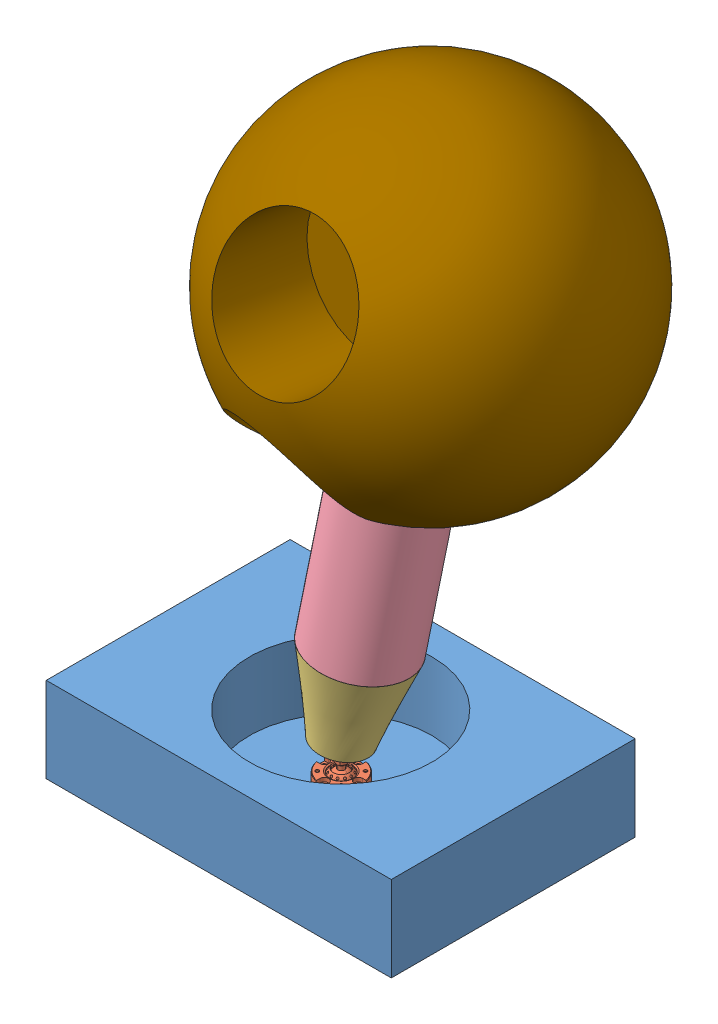
SolidWorks assembly full_model1, configuration Default. Lengths in mm.
Overall size (254.38 392.52 231.48).
52 component instances, 9 part files, 21 mates.
Components (placement in the parent):
- torso-1: torso [Default] x (-1 0 0) z (0 0 -1) size (202.29 50 142.99)
- SR JOINT - SRJ006C-1: SR JOINT - SRJ006C [Default] at (0.3693 15.1617 0) x (0 -1 0) z (0 0 1) size (26.94 25.01 25.01)
- cone-1: cone [Default] at (7.2631 84.0209 -4.0174) x (-0.271209 0.115653 0.955547) z (0.952594 -0.109957 0.283679) size (57.45 50 58.36)
- neck-1: neck [Default] at (21.0508 182.7394 -12.0523) x (0.07218 -0.090923 -0.993239) z (-0.987816 0.131145 -0.083791) size (55 152.51 55)
- 4200-2: 4200 [Default] at (40.0164 210.3951 -13.2057) x (-0.987816 0.131145 -0.083791) z (-0.15192 -0.929416 0.336313) size (14 30.03 30.03)
  - 4200_3-1: 4200_3 [Default] at (3.5 -8.0902 -5.8779) size (4.76 4.76 4.76)
  - 4200_3-2: 4200_3 [Default] at (3.5 -3.0902 -9.5106) size (4.76 4.76 4.76)
  - 4200_3-3: 4200_3 [Default] at (3.5 3.0902 -9.5106) size (4.76 4.76 4.76)
  - 4200_3-4: 4200_3 [Default] at (3.5 8.0902 -5.8779) size (4.76 4.76 4.76)
  - 4200_3-5: 4200_3 [Default] at (3.5 10 0) size (4.76 4.76 4.76)
  - 4200_3-6: 4200_3 [Default] at (3.5 8.0902 5.8779) size (4.76 4.76 4.76)
  - 4200_3-7: 4200_3 [Default] at (3.5 3.0902 9.5106) size (4.76 4.76 4.76)
  - 4200_3-8: 4200_3 [Default] at (3.5 -3.0902 9.5106) size (4.76 4.76 4.76)
  - 4200_3-9: 4200_3 [Default] at (3.5 -8.0902 5.8779) size (4.76 4.76 4.76)
  - 4200_3-10: 4200_3 [Default] at (3.5 -10 0) size (4.76 4.76 4.76)
  - 4200_3-11: 4200_3 [Default] at (10.5 -8.0902 -5.8779) size (4.76 4.76 4.76)
  - 4200_3-12: 4200_3 [Default] at (10.5 -3.0902 -9.5106) size (4.76 4.76 4.76)
  - 4200_3-13: 4200_3 [Default] at (10.5 3.0902 -9.5106) size (4.76 4.76 4.76)
  - 4200_3-14: 4200_3 [Default] at (10.5 8.0902 -5.8779) size (4.76 4.76 4.76)
  - 4200_3-15: 4200_3 [Default] at (10.5 10 0) size (4.76 4.76 4.76)
  - 4200_3-16: 4200_3 [Default] at (10.5 8.0902 5.8779) size (4.76 4.76 4.76)
  - 4200_3-17: 4200_3 [Default] at (10.5 3.0902 9.5106) size (4.76 4.76 4.76)
  - 4200_3-18: 4200_3 [Default] at (10.5 -3.0902 9.5106) size (4.76 4.76 4.76)
  - 4200_3-19: 4200_3 [Default] at (10.5 -8.0902 5.8779) size (4.76 4.76 4.76)
  - 4200_3-20: 4200_3 [Default] at (10.5 -10 0) size (4.76 4.76 4.76)
  - 4200_24-1: 4200_24 [Default] at (14 0 0) x (-1 0 0) z (0 0 1) size (14 30.03 30.03)
  - 4200_26-1: 4200_26 [Default] at origin size (14 17 17)
- 4200-1: 4200 [Default] at (24.1897 212.4963 -14.5482) x (-0.987816 0.131145 -0.083791) z (-0.010835 0.479146 0.877668) size (14 30.03 30.03)
  - 4200_3-1: 4200_3 [Default] at (3.5 -8.0902 -5.8779) size (4.76 4.76 4.76)
  - 4200_3-2: 4200_3 [Default] at (3.5 -3.0902 -9.5106) size (4.76 4.76 4.76)
  - 4200_3-3: 4200_3 [Default] at (3.5 3.0902 -9.5106) size (4.76 4.76 4.76)
  - 4200_3-4: 4200_3 [Default] at (3.5 8.0902 -5.8779) size (4.76 4.76 4.76)
  - 4200_3-5: 4200_3 [Default] at (3.5 10 0) size (4.76 4.76 4.76)
  - 4200_3-6: 4200_3 [Default] at (3.5 8.0902 5.8779) size (4.76 4.76 4.76)
  - 4200_3-7: 4200_3 [Default] at (3.5 3.0902 9.5106) size (4.76 4.76 4.76)
  - 4200_3-8: 4200_3 [Default] at (3.5 -3.0902 9.5106) size (4.76 4.76 4.76)
  - 4200_3-9: 4200_3 [Default] at (3.5 -8.0902 5.8779) size (4.76 4.76 4.76)
  - 4200_3-10: 4200_3 [Default] at (3.5 -10 0) size (4.76 4.76 4.76)
  - 4200_3-11: 4200_3 [Default] at (10.5 -8.0902 -5.8779) size (4.76 4.76 4.76)
  - 4200_3-12: 4200_3 [Default] at (10.5 -3.0902 -9.5106) size (4.76 4.76 4.76)
  - 4200_3-13: 4200_3 [Default] at (10.5 3.0902 -9.5106) size (4.76 4.76 4.76)
  - 4200_3-14: 4200_3 [Default] at (10.5 8.0902 -5.8779) size (4.76 4.76 4.76)
  - 4200_3-15: 4200_3 [Default] at (10.5 10 0) size (4.76 4.76 4.76)
  - 4200_3-16: 4200_3 [Default] at (10.5 8.0902 5.8779) size (4.76 4.76 4.76)
  - 4200_3-17: 4200_3 [Default] at (10.5 3.0902 9.5106) size (4.76 4.76 4.76)
  - 4200_3-18: 4200_3 [Default] at (10.5 -3.0902 9.5106) size (4.76 4.76 4.76)
  - 4200_3-19: 4200_3 [Default] at (10.5 -8.0902 5.8779) size (4.76 4.76 4.76)
  - 4200_3-20: 4200_3 [Default] at (10.5 -10 0) size (4.76 4.76 4.76)
  - 4200_24-1: 4200_24 [Default] at (14 0 0) x (-1 0 0) z (0 0 1) size (14 30.03 30.03)
  - 4200_26-1: 4200_26 [Default] at origin size (14 17 17)
- revolute joint_simple-1: revolute joint_simple [Default] at (-38.4512 222.1926 -24.7002) x (-0.025533 -0.667682 -0.744008) z (0.987816 -0.131145 0.083791) size (11 11 130)
- head-1: head [Default] at (33.4502 271.5962 -19.2853) x (-0.987816 0.131145 -0.083791) z (0.137877 0.987185 -0.080349) size (200 200 200)
Mates (geometry in assembly coordinates):
- Concentric15: concentric aligned: circle of cone-1; circle of neck-1
- Coincident33: coincident: point of assembly; point of cone-1; point of SR JOINT - SRJ006C-1
- Tangent1: tangent: plane of cone-1 through (7.2631 84.0209 -4.0174) normal (0.137877 0.987185 -0.080349); circle of neck-1
- Concentric19: concentric anti-aligned: cylinder of neck-1 through (40.0164 210.3951 -13.2057) axis (-0.987816 0.131145 -0.083791) radius 16; cylinder of 4200-2/4200_24-1 through (40.0164 210.3951 -13.2057) axis (0.987816 -0.131145 0.083791) radius 15
- Concentric20: concentric aligned: cylinder of neck-1 through (10.3603 214.3323 -15.7213) axis (0.987816 -0.131145 0.083791) radius 16; cylinder of 4200-1/4200_24-1 through (24.1897 212.4963 -14.5482) axis (0.987816 -0.131145 0.083791) radius 15
- Concentric23: concentric aligned: circle of neck-1; cylinder of revolute joint_simple-1 through (89.3856 203.8407 -9.018) axis (-0.987816 0.131145 -0.083791) radius 5.5
- Coincident35: coincident anti-aligned: plane of torso-1 through (0 0 0) normal (0 0 -1)
- Coincident36: coincident aligned: plane of torso-1 through (0 0 0) normal (0 1 0)
- Coincident37: coincident anti-aligned: plane of torso-1 through (0 0 0) normal (-1 0 0)
- Lock5: lock: unknown of torso-1; unknown of SR JOINT - SRJ006C-1
- Coincident43: coincident aligned: plane of neck-1 through (40.0164 210.3951 -13.2057) normal (0.987816 -0.131145 0.083791); plane of 4200-2/4200_24-1 through (39.628 214.3619 -2.4185) normal (0.987816 -0.131145 0.083791)
- Coincident44: coincident aligned: plane of neck-1 through (10.3603 214.3323 -15.7213) normal (-0.987816 0.131145 -0.083791); plane of 4200-1/4200_24-1 through (12.5338 226.4827 -22.3277) normal (-0.987816 0.131145 -0.083791)
- Distance2: distance = 50 mm aligned: plane of revolute joint_simple-1 through (-39.0305 220.8896 -19.9108) normal (-0.987816 0.131145 -0.083791); plane of neck-1 through (10.3603 214.3323 -15.7213) normal (-0.987816 0.131145 -0.083791)
- Coincident46: coincident aligned: plane of head-1 through (-39.0305 220.8896 -19.9108) normal (0.987816 -0.131145 0.083791); circle of revolute joint_simple-1
- Coincident47: coincident anti-aligned: plane of head-1 through (-39.0305 220.8896 -19.9108) normal (0.987816 -0.131145 0.083791); plane of revolute joint_simple-1 through (-39.0305 220.8896 -19.9108) normal (-0.987816 0.131145 -0.083791)
- Concentric27: concentric aligned: cylinder of revolute joint_simple-1 through (89.3856 203.8407 -9.018) axis (-0.987816 0.131145 -0.083791) radius 5.5; cylinder of head-1 through (89.3856 203.8407 -9.018) axis (-0.987816 0.131145 -0.083791) radius 12
- Coincident48: coincident anti-aligned: unknown of neck-1
- Parallel4: parallel aligned: unknown of neck-1
- Parallel5: parallel anti-aligned: plane of neck-1 through (21.0508 182.7394 -12.0523) normal (-0.137877 -0.987185 0.080349); plane of head-1 through (33.4502 271.5962 -19.2853) normal (0.137877 0.987185 -0.080349)
- LimitAngle5: limit planar angle = 0.160266 rad aligned: plane of cone-1 through (7.2631 84.0209 -4.0174) normal (0.137877 0.987185 -0.080349); plane of torso-1 through (0 60 0) normal (0 1 0)
- LimitAngle7: limit planar angle = 0 rad anti-aligned: plane of head-1 through (33.4502 271.5962 -19.2853) normal (0.137877 0.987185 -0.080349); plane of neck-1 through (21.0508 182.7394 -12.0523) normal (-0.137877 -0.987185 0.080349)
